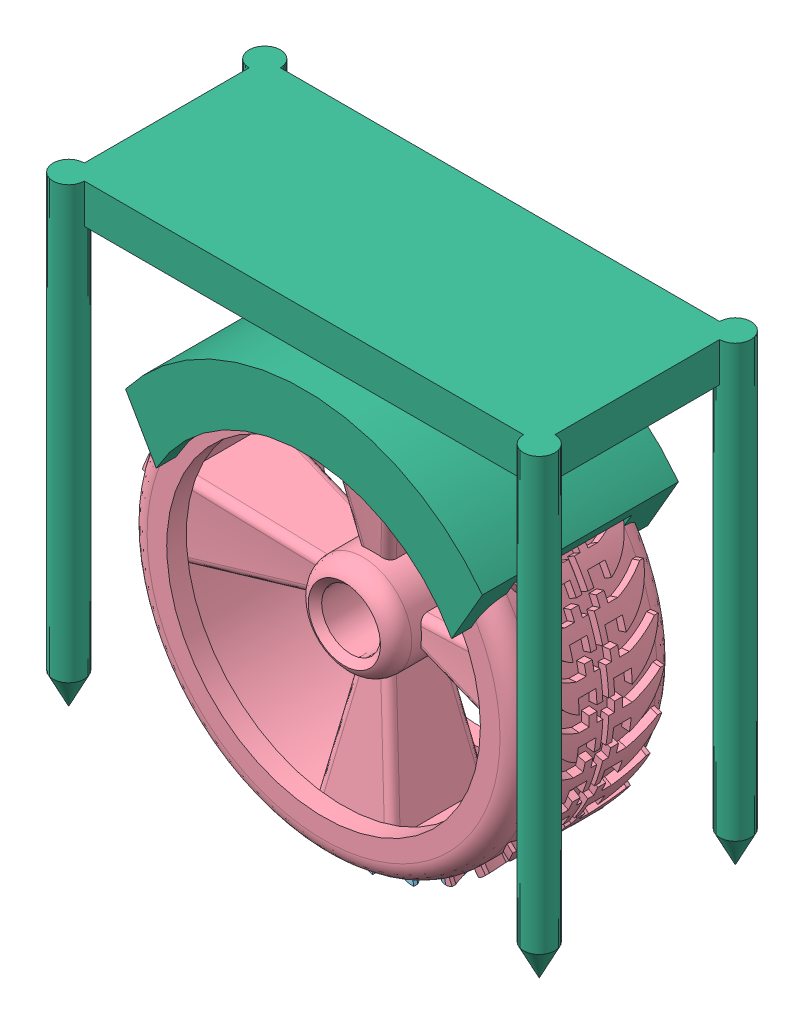
SolidWorks assembly assembly_tyre, configuration Default. Lengths in mm.
Overall size (128 127.08 58).
7 component instances, 7 part files, 18 mates.
Components (placement in the parent):
- tango-2: tango [Default] at (12.1317 30.0832 13.3307) x (1 0 0) z (0 0 -1) size (50 10.2 45) (hidden)
- Part2-CNT-3: Part2-CNT [Default] at (12.1317 30.0832 3.3307) x (1 0 0) z (0 1 0) size (40 10 4.87)
- Part2-IL-1: Part2-IL [Default] at (12.1317 30.0832 -16.6693) x (-1 0 0) z (0 1 0) size (50 30 8.52)
- Part2_CNT-Upper-Shorter-3: Part2_CNT-Upper-Shorter [Default] at (12.1317 30.0832 -11.6693) x (-1 0 0) z (0 0 1) size (10 0.66 20)
- Tyre_threaded-3: Tyre_threaded [Default] at (12.1317 30.0832 -21.6693) x (0 0 1) z (1 0 0) size (40 104.07 104.46)
- top_layer-1: top_layer [Default] at (12.1317 30.0832 13.3307) x (1 0 0) z (0 0 -1) size (51.81 9.62 32.78)
- substrate-3: substrate [Default] at (12.1317 105.0832 -1.6693) size (128 118 58)
Mates (geometry in assembly coordinates):
- Concentric4: concentric aligned: cylinder of tango-2 through (12.1317 30.0832 -16.6693) axis (0 0 1) radius 48; cylinder of Part2-CNT-3 through (12.1317 30.0832 1.3307) axis (0 0 1) radius 48
- Concentric6: concentric anti-aligned: cylinder of tango-2 through (12.1317 30.0832 -16.6693) axis (0 0 1) radius 48; cylinder of Part2-IL-1 through (12.1317 30.0832 13.3307) axis (0 0 -1) radius 48
- Coincident24: coincident anti-aligned: plane of Part2-IL-1 through (17.1317 -8.8914 8.3307) normal (0 0 -1); plane of Part2_CNT-Upper-Shorter-3 through (12.1317 30.0832 8.3307) normal (0 0 1)
- Coincident25: coincident anti-aligned: plane of Part2-IL-1 through (7.1317 -8.8914 -11.6693) normal (1 0 0); plane of Part2_CNT-Upper-Shorter-3 through (7.1317 -19.1636 8.3307) normal (-1 0 0)
- Concentric8: concentric aligned: cylinder of Part2-IL-1 through (12.1317 30.0832 13.3307) axis (0 0 -1) radius 49; cylinder of Part2_CNT-Upper-Shorter-3 through (12.1317 30.0832 8.3307) axis (0 0 -1) radius 49
- Coincident26: coincident anti-aligned: plane of tango-2 through (37.1317 127.0832 13.3307) normal (1 0 0); plane of Tyre_threaded-3 through (37.1317 86.1674 13.3307) normal (-1 0 0)
- Coincident27: coincident anti-aligned: plane of tango-2 through (12.1317 30.0832 -16.6693) normal (0 0 -1); plane of Tyre_threaded-3 through (37.1317 86.1674 -16.6693) normal (0 0 1)
- Concentric9: concentric anti-aligned: cylinder of tango-2 through (12.1317 30.0832 -16.6693) axis (0 0 1) radius 47; cylinder of Tyre_threaded-3 through (12.1317 30.0832 18.3307) axis (0 0 -1) radius 47
- Coincident30: coincident anti-aligned: plane of Tyre_threaded-3 through (37.1317 86.1674 -16.6693) normal (0 0 1); plane of top_layer-1 through (12.1317 30.0832 -16.6693) normal (0 0 -1)
- Coincident31: coincident anti-aligned: plane of Tyre_threaded-3 through (-12.8683 86.1674 13.3307) normal (1 0 0); plane of top_layer-1 through (-12.8683 -13.218 -16.6693) normal (-1 0 0)
- Concentric10: concentric anti-aligned: cylinder of Part2-IL-1 through (12.1317 30.0832 13.3307) axis (0 0 -1) radius 49.5; cylinder of top_layer-1 through (12.1317 30.0832 -16.6693) axis (0 0 1) radius 49.5
- Coincident33: coincident anti-aligned: plane of Part2-IL-1 through (12.1317 30.0832 13.3307) normal (0 0 1); plane of Tyre_threaded-3 through (37.1317 86.1674 13.3307) normal (0 0 -1)
- Coincident34: coincident anti-aligned: plane of Part2-IL-1 through (-12.8683 -12.6397 13.3307) normal (-1 0 0); plane of Tyre_threaded-3 through (-12.8683 86.1674 13.3307) normal (1 0 0)
- Concentric14: concentric anti-aligned: cylinder of Part2-CNT-3 through (12.1317 30.0832 -6.6693) axis (0 0 1) radius 48.5; cylinder of Part2-IL-1 through (12.1317 30.0832 13.3307) axis (0 0 -1) radius 48.5
- Coincident35: coincident anti-aligned: plane of Part2-CNT-3 through (12.1317 30.0832 -4.6693) normal (0 0 1); plane of Part2-IL-1 through (-7.8683 -21.4178 -4.6693) normal (0 0 -1)
- Coincident36: coincident anti-aligned: plane of Part2-CNT-3 through (-7.8683 -14.101 -6.6693) normal (-1 0 0); plane of Part2-IL-1 through (-7.8683 -21.4178 -4.6693) normal (1 0 0)
- Concentric17: concentric anti-aligned: cylinder of Tyre_threaded-3 through (12.1317 30.0832 18.3307) axis (0 0 -1) radius 45; cylinder of substrate-3 through (12.1317 30.0832 38.7477) axis (0 0 1) radius 53.5
- Coincident38: coincident anti-aligned: plane of Tyre_threaded-3 through (12.1317 30.0832 18.3307) normal (0 0 1); plane of substrate-3 through (62.1317 30.0832 18.3307) normal (0 0 -1)
